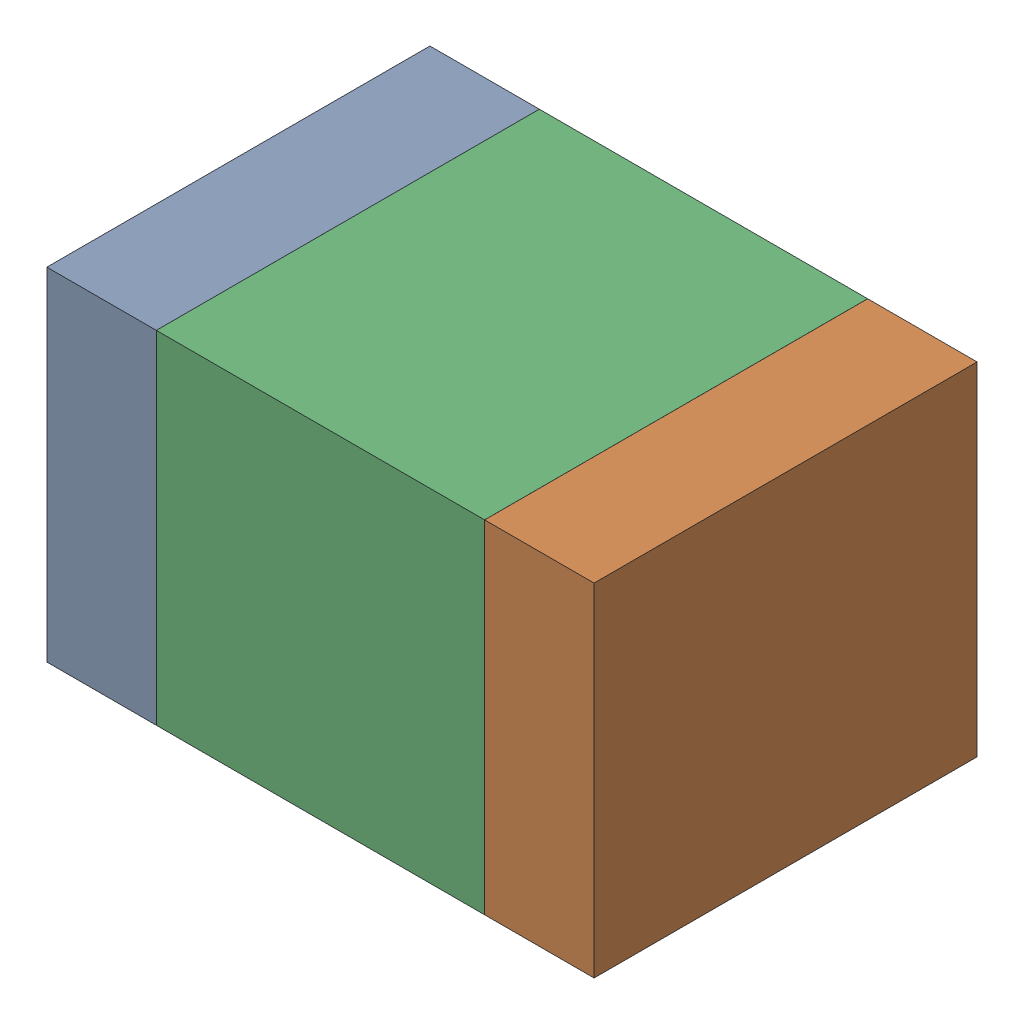
SolidWorks assembly C1, configuration ﾃﾞﾌｫﾙﾄ. Lengths in mm.
Overall size (2 1.25 1.4).
6 component instances, 2 part files, 0 mates.
Components (placement in the parent):
- 689248456-1: 689248456 [ﾃﾞﾌｫﾙﾄ] at (20.7001 29.5 0) size (0.4 1.25 1.4)
  - Extruded-1: Extruded [ﾃﾞﾌｫﾙﾄ] at origin size (0.4 1.25 1.4)
- 689248456-2: 689248456 [ﾃﾞﾌｫﾙﾄ] at (22.3001 29.5 0) size (0.4 1.25 1.4)
  - Extruded-1: Extruded [ﾃﾞﾌｫﾙﾄ] at origin size (0.4 1.25 1.4)
- 689259200-1: 689259200 [ﾃﾞﾌｫﾙﾄ] at (21.5 29.5 0) size (1.2 1.25 1.4)
  - Extruded_2-1: Extruded_2 [ﾃﾞﾌｫﾙﾄ] at origin size (1.2 1.25 1.4)
